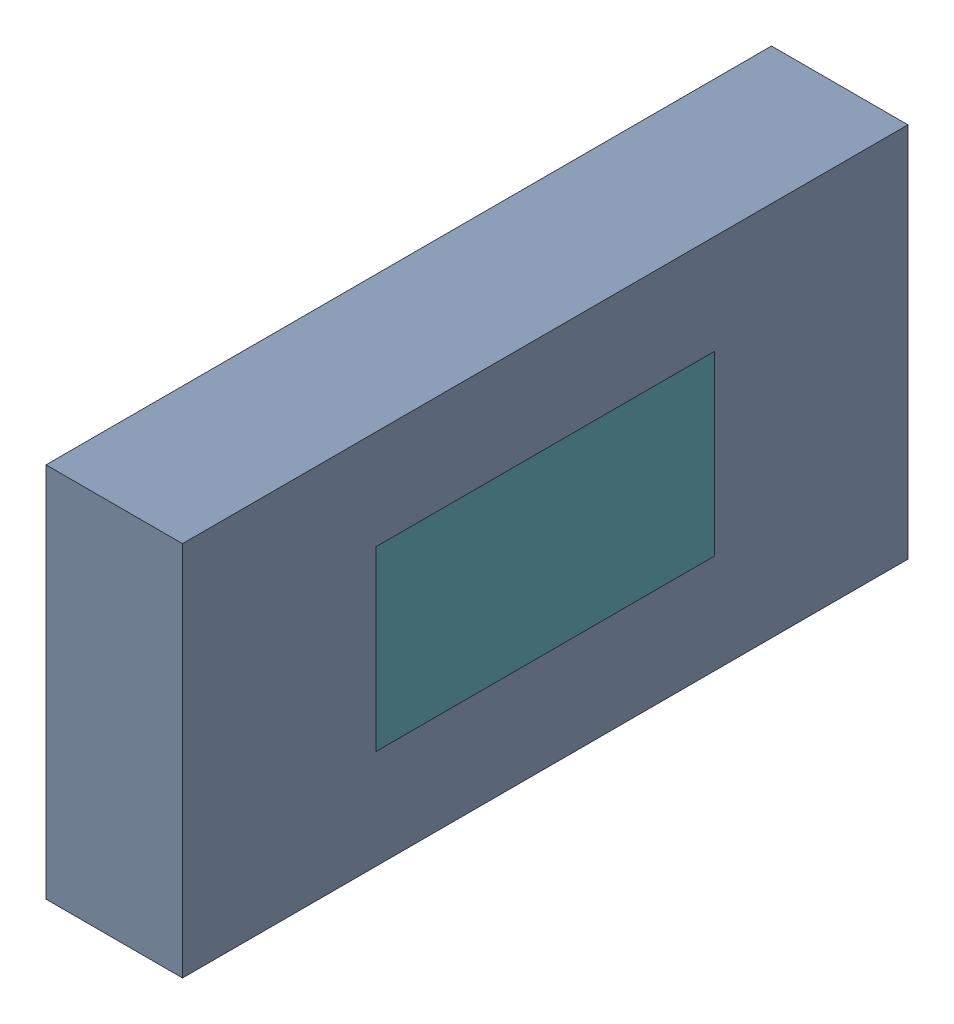
SolidWorks assembly c1, configuration Default. Lengths in mm.
Overall size (0.33 0.7 1.35).
25 component instances, 7 part files, 0 mates.
Components (placement in the parent):
- 6701982208-1:  [Default] at (27.7 14.8 0) (suppressed, hidden)
- 6327398464-1: 6327398464 [Default] at (4.2287 8.85 -2.9931) x (0 0 -1) z (1 0 0) size (1.35 0.7 0.25)
  - 6701982208-1:  [Default] at (27.7 14.8 0) (suppressed, hidden)
  - Extruded-15-1: Extruded-15 [Default] at origin size (1.35 0.7 0.25)
- 6327397888-1: 6327397888 [Default] at (4.2287 8.85 -2.9931) x (0 0 -1) z (1 0 0) size (0.63 0.33 0.25)
  - 6701982208-1:  [Default] at (27.7 14.8 0) (suppressed, hidden)
  - Extruded-16-1: Extruded-16 [Default] at origin size (0.63 0.33 0.25)
- 6327398080-1: 6327398080 [Default] at (4.2287 8.85 -2.9931) x (0 0 -1) z (1 0 0) size (0.73 0.43 0.25)
  - 6701982208-1:  [Default] at (27.7 14.8 0) (suppressed, hidden)
  - Extruded-17-1: Extruded-17 [Default] at origin size (0.73 0.43 0.25)
- 6327398272-1: 6327398272 [Default] at (4.2287 8.85 -2.9931) x (0 0 -1) z (1 0 0) size (1.25 0.6 0.25)
  - 6701982208-1:  [Default] at (27.7 14.8 0) (suppressed, hidden)
  - Extruded-18-1: Extruded-18 [Default] at origin size (1.25 0.6 0.25)
- 6327398464-2: 6327398464 [Default] at (4.2287 8.85 -2.9931) x (0 0 -1) z (1 0 0) size (1.35 0.7 0.25)
  - 6701982208-1:  [Default] at (27.7 14.8 0) (suppressed, hidden)
  - Extruded-15-1: Extruded-15 [Default] at origin size (1.35 0.7 0.25)
- 6327398656-1: 6327398656 [Default] at (4.2287 8.85 -2.9931) x (0 0 -1) z (1 0 0) size (1.15 0.5 0.25)
  - 6701982208-1:  [Default] at (27.7 14.8 0) (suppressed, hidden)
  - Extruded-19-1: Extruded-19 [Default] at origin size (1.15 0.5 0.25)
- 6327398848-1: 6327398848 [Default] at (4.1527 8.85 -2.9931) x (0 0 -1) z (1 0 0) size (0.63 0.33 0.33)
  - 6701982208-1:  [Default] at (27.7 14.8 0) (suppressed, hidden)
  - Extruded-20-1: Extruded-20 [Default] at origin size (0.63 0.33 0.33)
- 6327400768-1: 6327400768 [Default] at (4.2287 8.85 -2.9931) x (0 0 -1) z (1 0 0) size (0.33 0.33 0.25)
  - 6701982208-1:  [Default] at (27.7 14.8 0) (suppressed, hidden)
  - Extruded-6-1: Extruded-6 [Default] at origin size (0.33 0.33 0.25)
